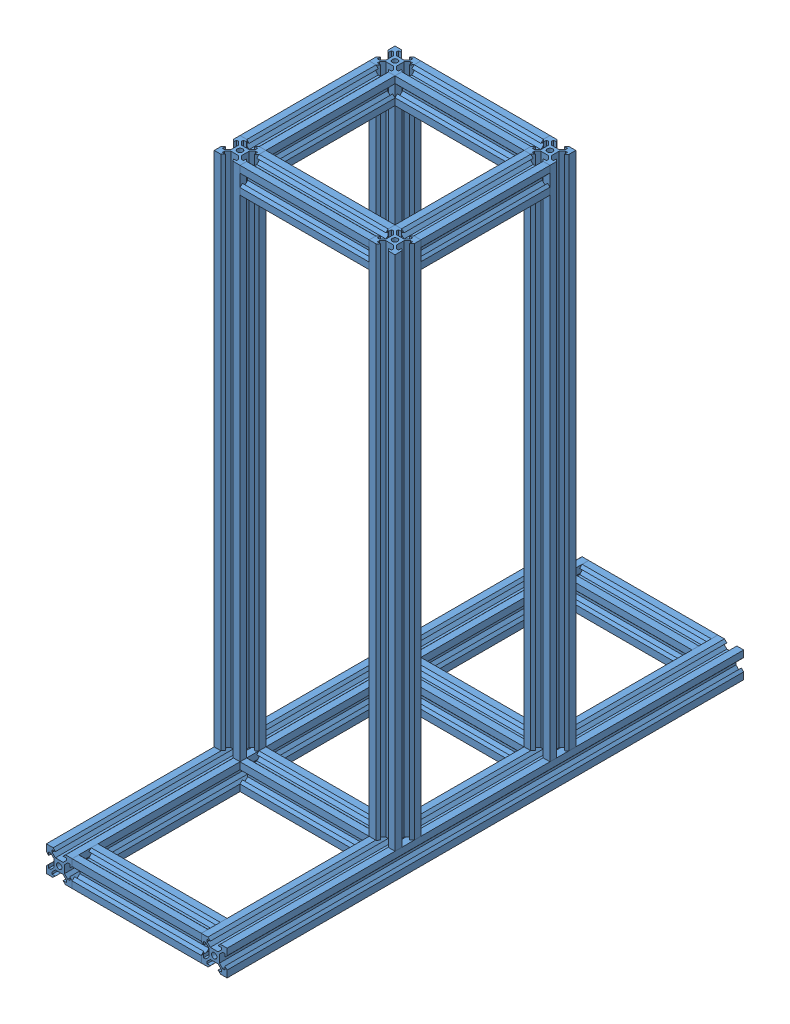
SolidWorks assembly Montagem1, configuration Valor predeterminado. Lengths in mm.
Overall size (140 420 400).
14 component instances, 1 part files, 28 mates.
Components (placement in the parent):
- Perfil_20x20mm-3: Perfil_20x20mm [100mm] at (50 10 190) x (0 1 0) z (0 0 1) size (20 100 20)
- Perfil_20x20mm-6: Perfil_20x20mm [100mm] at (-50 10 -190) x (0 1 0) z (0 0 -1) size (20 100 20)
- Perfil_20x20mm-7: Perfil_20x20mm [400mm] at (-60 10 -200) x (0 1 0) z (1 0 0) size (20 400 20)
- Perfil_20x20mm-8: Perfil_20x20mm [400mm] at (60 10 200) x (0 1 0) z (-1 0 0) size (20 400 20)
- Perfil_20x20mm-9: Perfil_20x20mm [400mm] at (-60 20 60) size (20 400 20)
- Perfil_20x20mm-10: Perfil_20x20mm [400mm] at (-60 420 -60) x (1 0 0) z (0 0 -1) size (20 400 20)
- Perfil_20x20mm-11: Perfil_20x20mm [400mm] at (60 420 60) x (-1 0 0) z (0 0 1) size (20 400 20)
- Perfil_20x20mm-12: Perfil_20x20mm [400mm] at (60 20 -60) x (-1 0 0) z (0 0 -1) size (20 400 20)
- Perfil_20x20mm-13: Perfil_20x20mm [100mm] at (50 410 60) x (0 1 0) z (0 0 1) size (20 100 20)
- Perfil_20x20mm-14: Perfil_20x20mm [100mm] at (-50 410 -60) x (0 1 0) z (0 0 -1) size (20 100 20)
- Perfil_20x20mm-15: Perfil_20x20mm [100mm] at (-60 410 -50) x (1 0 0) z (0 -1 0) size (20 100 20)
- Perfil_20x20mm-16: Perfil_20x20mm [100mm] at (60 410 50) x (-1 0 0) z (0 -1 0) size (20 100 20)
- Perfil_20x20mm-17: Perfil_20x20mm [100mm] at (50 10 60) x (0 1 0) z (0 0 1) size (20 100 20)
- Perfil_20x20mm-18: Perfil_20x20mm [100mm] at (-50 10 -60) x (0 1 0) z (0 0 -1) size (20 100 20)
Mates (geometry in assembly coordinates):
- Coincidente1: coincident aligned: plane of ? through (96.1354 108.653 486.2239) normal (0 0 1); plane of ? through (176.1354 108.653 486.2239) normal (0 0 1)
- Coincidente2: coincident aligned: plane of ? through (96.1354 118.653 486.2239) normal (0 1 0); plane of ? through (176.1354 118.653 486.2239) normal (0 1 0)
- Coincidente7: coincident aligned: plane of ? through (186.1354 108.653 486.2239) normal (1 0 0); plane of Perfil_20x20mm-3 through (186.1354 108.653 496.2239) normal (1 0 0)
- Coincidente8: coincident anti-aligned: plane of ? through (176.1354 108.653 486.2239) normal (0 0 1); plane of Perfil_20x20mm-3 through (86.1354 108.653 486.2239) normal (0 0 -1)
- Coincidente9: coincident aligned: plane of ? through (176.1354 118.653 486.2239) normal (0 1 0); plane of Perfil_20x20mm-3 through (86.1354 118.653 496.2239) normal (0 1 0)
- Coincidente10: coincident aligned: plane of ? through (86.1354 108.653 486.2239) normal (-1 0 0); plane of Perfil_20x20mm-3 through (86.1354 108.653 496.2239) normal (-1 0 0)
- Coincidente11: coincident aligned: plane of ? through (186.1354 108.653 486.2239) normal (1 0 0); plane of ? through (186.1354 108.653 76.2239) normal (1 0 0)
- Coincidente12: coincident aligned: plane of ? through (176.1354 118.653 486.2239) normal (0 1 0); plane of ? through (86.1354 118.653 76.2239) normal (0 1 0)
- Coincidente13: coincident anti-aligned: plane of ? through (176.1354 108.653 86.2239) normal (0 0 -1); plane of ? through (86.1354 108.653 86.2239) normal (0 0 1)
- Coincidente14: coincident anti-aligned: plane of ? through (176.1354 118.653 486.2239) normal (0 1 0); plane of ? through (51.2555 118.653 362.9057) normal (0 -1 0)
- Distância1: distance = 180 mm anti-aligned: plane of Perfil_20x20mm-3 through (-50 10 180) normal (0 0 -1); plane of assembly through (0 0 0) normal (0 0 1)
- Coincidente16: coincident anti-aligned: plane of Perfil_20x20mm-3 through (-50 0 190) normal (0 -1 0); plane of assembly through (0 0 0) normal (0 1 0)
- Simétrico1: symmetric aligned: plane of Perfil_20x20mm-3 through (50 10 190) normal (1 0 0); plane of Perfil_20x20mm-3 through (-50 10 190) normal (-1 0 0); plane of assembly through (0 0 0) normal (1 0 0)
- Coincidente18: coincident aligned: plane of Perfil_20x20mm-3 through (-50 20 190) normal (0 1 0); plane of Perfil_20x20mm-7 through (-60 20 200) normal (0 1 0)
- Coincidente19: coincident aligned: plane of Perfil_20x20mm-3 through (-50 10 200) normal (0 0 1); plane of Perfil_20x20mm-7 through (-60 10 200) normal (0 0 1)
- Coincidente20: coincident anti-aligned: plane of Perfil_20x20mm-3 through (-50 10 190) normal (-1 0 0); plane of Perfil_20x20mm-7 through (-50 10 200) normal (1 0 0)
- Coincidente21: coincident aligned: plane of Perfil_20x20mm-7 through (-50 10 200) normal (1 0 0); plane of Perfil_20x20mm-9 through (-50 420 60) normal (1 0 0)
- Coincidente22: coincident anti-aligned: plane of Perfil_20x20mm-7 through (-60 20 200) normal (0 1 0); plane of Perfil_20x20mm-9 through (-60 20 60) normal (0 -1 0)
- Coincidente23: coincident aligned: plane of Perfil_20x20mm-11 through (60 420 60) normal (0 1 0); plane of Perfil_20x20mm-13 through (-50 420 60) normal (0 1 0)
- Coincidente24: coincident anti-aligned: plane of Perfil_20x20mm-9 through (-50 420 60) normal (1 0 0); plane of Perfil_20x20mm-13 through (-50 410 60) normal (-1 0 0)
- Coincidente25: coincident aligned: plane of Perfil_20x20mm-11 through (60 20 70) normal (0 0 1); plane of Perfil_20x20mm-13 through (-50 410 70) normal (0 0 1)
- Coincidente27: coincident aligned: plane of Perfil_20x20mm-9 through (-60 420 60) normal (0 1 0); plane of Perfil_20x20mm-15 through (-60 420 50) normal (0 1 0)
- Coincidente28: coincident anti-aligned: plane of Perfil_20x20mm-10 through (-60 20 -50) normal (0 0 1); plane of Perfil_20x20mm-15 through (-60 410 -50) normal (0 0 -1)
- Coincidente29: coincident anti-aligned: plane of Perfil_20x20mm-9 through (-60 420 50) normal (0 0 -1); plane of Perfil_20x20mm-15 through (-60 410 50) normal (0 0 1)
- Coincidente30: coincident aligned: plane of Perfil_20x20mm-9 through (-70 420 60) normal (-1 0 0); plane of Perfil_20x20mm-15 through (-70 410 50) normal (-1 0 0)
- Coincidente31: coincident aligned: plane of Perfil_20x20mm-7 through (-60 0 200) normal (0 -1 0); plane of Perfil_20x20mm-17 through (-50 0 60) normal (0 -1 0)
- Coincidente32: coincident aligned: plane of Perfil_20x20mm-9 through (-60 420 70) normal (0 0 1); plane of Perfil_20x20mm-17 through (-50 10 70) normal (0 0 1)
- Coincidente33: coincident anti-aligned: plane of Perfil_20x20mm-8 through (50 10 -200) normal (-1 0 0); plane of Perfil_20x20mm-17 through (50 10 60) normal (1 0 0)
